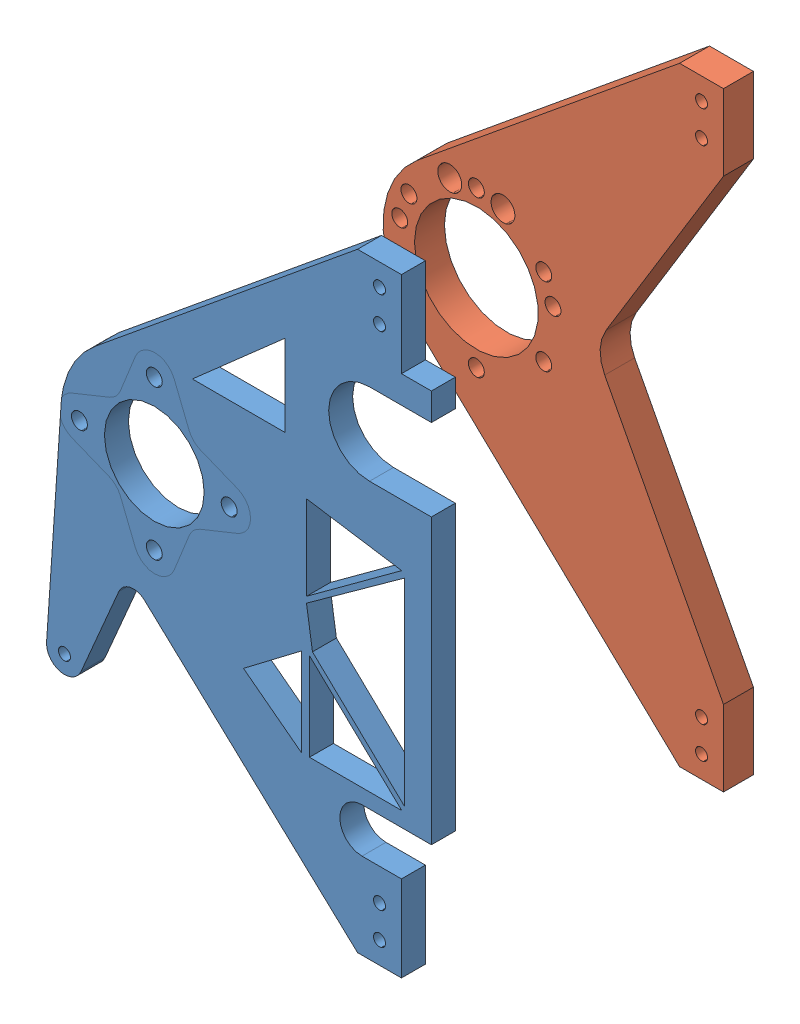
SolidWorks assembly Motor_Assembly, configuration Default. Lengths in mm.
Overall size (192.83 305.21 176.37).
2 component instances, 2 part files, 2 mates.
Components (placement in the parent):
- Left Motor Mounting-1: Left Motor Mounting [Default] at (93.9275 209.0439 188.4804) size (192.83 305.21 12)
- Right Motor Mounting-1: Right Motor Mounting [Default] at (93.9275 209.0439 24.1149) size (170.57 305.21 15)
Mates (geometry in assembly coordinates):
- Parallel1: parallel aligned: cylinder of Left Motor Mounting-1 through (93.9275 209.0439 200.4804) axis (0 0 -1) radius 25; cylinder of Right Motor Mounting-1 through (93.9275 209.0439 39.1149) axis (0 0 -1) radius 31
- Concentric6: concentric aligned: cylinder of Left Motor Mounting-1 through (93.9275 209.0439 200.4804) axis (0 0 -1) radius 25; cylinder of Right Motor Mounting-1 through (93.9275 209.0439 39.1149) axis (0 0 -1) radius 31
